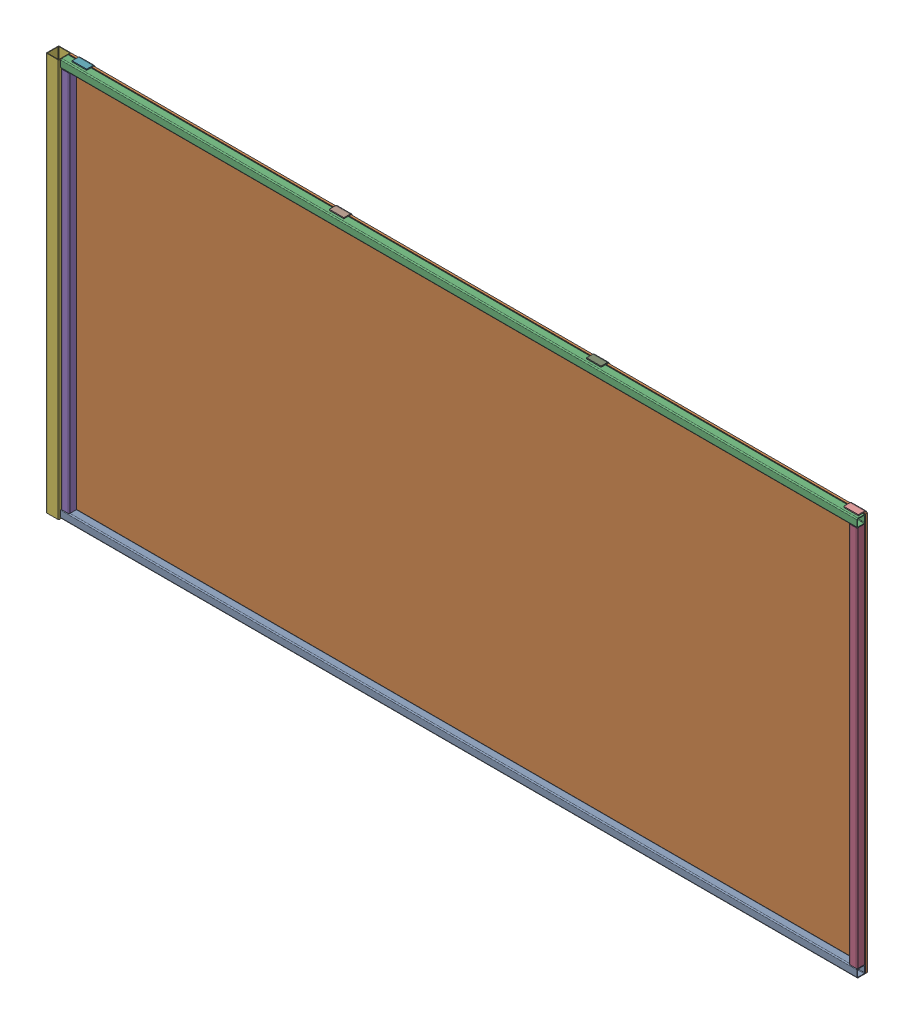
SolidWorks assembly Wall Assembly, configuration Default. Lengths in mm.
Overall size (2476.5 1222.38 41.27).
10 component instances, 5 part files, 24 mates.
Components (placement in the parent):
- 8ft 1in Steel Bar-1: 8ft 1in Steel Bar [1471T534] at (1219.2 12.7 -12.7) x (0 0 1) z (-1 0 0) size (25.4 25.4 2438.4)
- Polycarbonate-1: Polycarbonate [8574K75] at (1219.2 609.6 -28.575) size (2438.4 1219.2 6.35)
- 8ft 1in Steel Bar-2: 8ft 1in Steel Bar [1471T534] at (1219.2 1206.5 -12.7) x (0 0 1) z (1 0 0) size (25.4 25.4 2438.4)
- 46in 1in Steel Bar-1: 46in 1in Steel Bar [1471T532] at (2425.7 584.2 -12.7) x (1 0 0) z (0 1 0) size (25.4 25.4 1168.4)
- 46in 1in Steel Bar-2: 46in 1in Steel Bar [1471T532] at (12.7 584.2 -12.7) x (1 0 0) z (0 1 0) size (25.4 25.4 1168.4)
- 4ft 1.5in Steel Bar-1: 4ft 1.5in Steel Bar [6527K573] at (-19.05 914.4 -12.7) x (0 -1 0) z (1 0 0) size (1219.2 38.1 38.1)
- Corner Bracket-1: Corner Bracket [2313N38] at (47.625 1171.575 -34.925) x (0 0 1) z (0 -1 0) size (25.4 44.45 50.8)
- Corner Bracket-2: Corner Bracket [2313N38] at (835.2367 1171.575 -34.925) x (0 0 1) z (0 -1 0) size (25.4 44.45 50.8)
- Corner Bracket-3: Corner Bracket [2313N38] at (1622.8483 1171.575 -34.925) x (0 0 1) z (0 -1 0) size (25.4 44.45 50.8)
- Corner Bracket-4: Corner Bracket [2313N38] at (2410.46 1171.575 -34.925) x (0 0 1) z (0 -1 0) size (25.4 44.45 50.8)
Mates (geometry in assembly coordinates):
- Coincident1: coincident aligned: plane of 8ft Steel Bar-1 through (0 0 0) normal (0 0 1)
- Coincident2: coincident anti-aligned: plane of 8ft Steel Bar-1 through (0 0 0) normal (0 -1 0)
- Coincident3: coincident anti-aligned: plane of 8ft Steel Bar-1 through (0 12.7 -12.7) normal (-1 0 0)
- Coincident4: coincident anti-aligned: plane of 8ft Steel Bar-1 through (0 0 -25.4) normal (0 0 -1); plane of 8574K75_Clear Impact-Resistant Polycarbonate-1 through (1219.2 609.6 -25.4) normal (0 0 1)
- Coincident5: coincident aligned: plane of 8ft Steel Bar-1 through (2438.4 12.7 -12.7) normal (1 0 0); plane of 8574K75_Clear Impact-Resistant Polycarbonate-1 through (2438.4 0 -25.4) normal (1 0 0)
- Coincident6: coincident aligned: plane of 8ft Steel Bar-1 through (0 0 0) normal (0 -1 0); plane of 8574K75_Clear Impact-Resistant Polycarbonate-1 through (0 0 -25.4) normal (0 -1 0)
- Coincident7: coincident anti-aligned: plane of 8574K75_Clear Impact-Resistant Polycarbonate-1 through (1219.2 609.6 -25.4) normal (0 0 1); plane of 8ft Steel Bar-2 through (2438.4 1219.2 -25.4) normal (0 0 -1)
- Coincident8: coincident aligned: plane of 8574K75_Clear Impact-Resistant Polycarbonate-1 through (2438.4 0 -25.4) normal (1 0 0); plane of 8ft Steel Bar-2 through (2438.4 1206.5 -12.7) normal (1 0 0)
- Coincident9: coincident aligned: plane of 8574K75_Clear Impact-Resistant Polycarbonate-1 through (0 1219.2 -25.4) normal (0 1 0); plane of 8ft Steel Bar-2 through (2438.4 1219.2 0) normal (0 1 0)
- Coincident10: coincident anti-aligned: plane of 8574K75_Clear Impact-Resistant Polycarbonate-1 through (1219.2 609.6 -25.4) normal (0 0 1); plane of 4ft Steel Bar-2 through (25.4 1193.8 -25.4) normal (0 0 -1)
- Coincident11: coincident anti-aligned: plane of 8ft Steel Bar-2 through (2438.4 1193.8 0) normal (0 -1 0); plane of 4ft Steel Bar-2 through (12.7 1193.8 -12.7) normal (0 1 0)
- Coincident12: coincident aligned: plane of 8ft Steel Bar-2 through (0 1206.5 -12.7) normal (-1 0 0); plane of 4ft Steel Bar-2 through (0 1193.8 0) normal (-1 0 0)
- Coincident13: coincident anti-aligned: plane of 8574K75_Clear Impact-Resistant Polycarbonate-1 through (1219.2 609.6 -25.4) normal (0 0 1); plane of 4ft Steel Bar-1 through (2438.4 1193.8 -25.4) normal (0 0 -1)
- Coincident14: coincident aligned: plane of 8574K75_Clear Impact-Resistant Polycarbonate-1 through (2438.4 0 -25.4) normal (1 0 0); plane of 4ft Steel Bar-1 through (2438.4 1193.8 0) normal (1 0 0)
- Coincident15: coincident anti-aligned: plane of 8ft Steel Bar-2 through (2438.4 1193.8 0) normal (0 -1 0); plane of 4ft Steel Bar-1 through (2425.7 1193.8 -12.7) normal (0 1 0)
- Coincident16: coincident: plane of 4ft Steel Bar-2 through (0 1193.8 0) normal (-1 0 0); plane of 4ft Steel Bar-3 through (13.3319 284.362 -25.3428) normal (1 0 0)
- Coincident17: coincident: plane of 8574K75_Clear Impact-Resistant Polycarbonate-1 through (1219.2 609.6 -31.75) normal (0 0 -1); plane of 4ft Steel Bar-3 through (-12.0681 284.362 -25.3428) normal (0 0 -1)
- Coincident20: coincident aligned: plane of 8ft Steel Bar-2 through (2438.4 1219.2 0) normal (0 1 0); plane of 4ft Steel Bar-3 through (-12.7 1219.2 -19.05) normal (0 1 0)
- Coincident21: coincident anti-aligned: plane of 46in Steel Bar-2 through (0 1193.8 0) normal (-1 0 0); plane of 6527K573_Low-Carbon Steel Rectangular Tube-1 through (0 0 4.445) normal (1 0 0)
- Coincident22: coincident aligned: plane of 8574K75_Clear Impact-Resistant Polycarbonate-1 through (1219.2 609.6 -31.75) normal (0 0 -1); plane of 6527K573_Low-Carbon Steel Rectangular Tube-1 through (-36.195 0 -31.75) normal (0 0 -1)
- Coincident23: coincident aligned: plane of 8ft Steel Bar-2 through (2438.4 1219.2 0) normal (0 1 0); plane of 6527K573_Low-Carbon Steel Rectangular Tube-1 through (-38.1 1219.2 -31.75) normal (0 1 0)
- Coincident24: coincident anti-aligned: plane of 8ft 1in Steel Bar-2 through (2438.4 1219.2 0) normal (0 1 0); plane of Corner Bracket-1 through (69.85 1219.2 -34.925) normal (0 -1 0)
- Coincident25: coincident anti-aligned: plane of Polycarbonate-1 through (1219.2 609.6 -31.75) normal (0 0 -1); plane of Corner Bracket-1 through (69.85 1171.575 -31.75) normal (0 0 1)
- Coincident26: coincident anti-aligned: plane of 46in 1in Steel Bar-2 through (25.4 1193.8 0) normal (1 0 0); plane of Corner Bracket-1 through (25.4 1219.2 -34.925) normal (-1 0 0)
